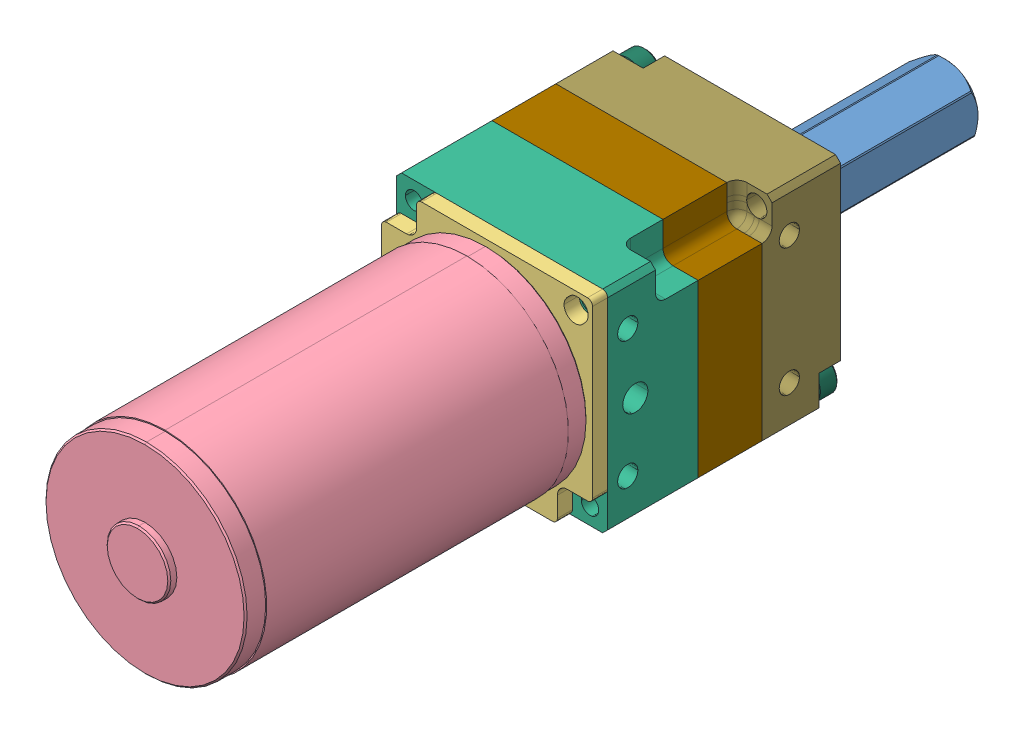
SolidWorks assembly VersaPlanetary-1-Stage-with-BAG-Motor.STEP, configuration Default. Lengths in mm.
Overall size (62.06 62.06 160.81).
22 component instances, 15 part files, 0 mates.
Components (placement in the parent):
- Ouput Shafts^VersaPlanetary_500 Hex.STEP-1: Ouput Shafts^VersaPlanetary_500 Hex.STEP [Default] at (0 0 -20.5526) x (-0.995515 -0.094608 0) z (0 0 -1) size (17 17 64.11)
  - 217-2625-003 Rev1.STEP-1: 217-2625-003 Rev1.STEP [Default] at origin size (17 17 64.11)
- 217-3564-000 Rev1_BAG.STEP-1: 217-3564-000 Rev1_BAG.STEP [Default] at (0 0 18) size (42 42 81.5)
  - 217-2625-011 Rev1.STEP-1: 217-2625-011 Rev1.STEP [Default] at (0 0 -5.25) x (1 0 0) z (0 -1 0) size (8.01 7.5 7.94)
  - 217-2822-003 Rev4.STEP-1: 217-2822-003 Rev4.STEP [Default] at (0 0 1.5) size (42 42 4.8)
  - 217-3351.STEP-1: 217-3351.STEP [Default] at (0 0 3) x (0 1 0) z (0 0 -1) size (40.4 40.4 81.5)
- Input Housing^VersaPlanetary.STEP-1: Input Housing^VersaPlanetary.STEP [Default] at (-18.5 13.6657 1) x (0 0 -1) z (-0.885621 0.464408 0) size (20 56.7 56.7)
  - PINL-M020-006-S.STEP-1: PINL-M020-006-S.STEP [Default] at origin size (6 2 2)
  - 217-2625-001 Rev1.STEP-1: 217-2625-001 Rev1.STEP [Default] at (-9.5 3.511 -22.7304) x (0 -0.464408 -0.885621) z (-1 0 0) size (42 42 18)
  - 217-2625-009 Rev1.STEP-1: 217-2625-009 Rev1.STEP [Default] at (-6.02 3.511 -22.7304) x (0 0.885621 -0.464408) z (1 0 0) size (18 18 13)
  - SSS1032-0125ZB_94105A824.STEP-1: SSS1032-0125ZB_94105A824.STEP [Default] at (-11.495 6.7192 -16.6126) x (-0.636804 0.682837 -0.35807) z (0 0.464408 0.885621) size (4.84 4.84 3.18)
- 217-2816 Rev1.STEP-1: 217-2816 Rev1.STEP [Default] at (0 0 -6.35) x (1 0 0) z (0 0 -1) size (42 42 14.51)
  - 217-2816-001 Rev1.STEP-1: 217-2816-001 Rev1.STEP [Default] at origin size (42 42 14.51)
- 217-2817 Rev1.STEP-1: 217-2817 Rev1.STEP [Default] at (0 0 -10.8) x (-0.517538 0.85566 0) z (0 0 -1) size (21.9 21.9 12.71)
  - 217-2724-001 Rev1_Sun_Driver01.STEP-1: 217-2724-001 Rev1_Sun_Driver01.STEP [Default] at (0 0 -6.375) x (0.984808 0.173648 0) z (0 0 1) size (18.9 18.9 12.71)
- 217-2742-001 Rev4.STEP-1: 217-2742-001 Rev4.STEP [Default] at (0 0 -19.9002) x (0 0 1) z (-1 0 0) size (7 28 28)
- 217-2742-001 Rev4.STEP-2: 217-2742-001 Rev4.STEP [Default] at (0 0 -28.305) x (0 0 1) z (-0.819238 -0.573454 0) size (7 28 28)
- 217-2625-002 Rev1.STEP-1: 217-2625-002 Rev1.STEP [Default] at (0 0 -6.2) x (-1 0 0) z (0 0 1) size (42 42 17.12)
- 217-2625-018 Rev1_98541A410.STEP-1: 217-2625-018 Rev1_98541A410.STEP [Default] at (0 0 -12.4002) x (0 0 -1) z (0.980859 -0.194721 0) size (1 19.6 17.4)
- 217-2625-017 Rev1_9714K61.STEP-1: 217-2625-017 Rev1_9714K61.STEP [Default] at (0 0 -20.9002) x (-0.695225 0.718792 0) z (-0.718792 -0.695225 0) size (28.51 4.98 27.43)
- SSA_SSA0832-1250ZC.STEP-1: SSA_SSA0832-1250ZC.STEP [Default] at (-17.5 17.5 -24.061) x (0.699203 0.714923 0) z (-0.714923 0.699203 0) size (6.73 35.81 6.73)
- SSA_SSA0832-1250ZC.STEP-2: SSA_SSA0832-1250ZC.STEP [Default] at (17.5 -17.5 -24.061) x (-0.999999 0.001665 0) z (-0.001665 -0.999999 0) size (6.73 35.81 6.73)
